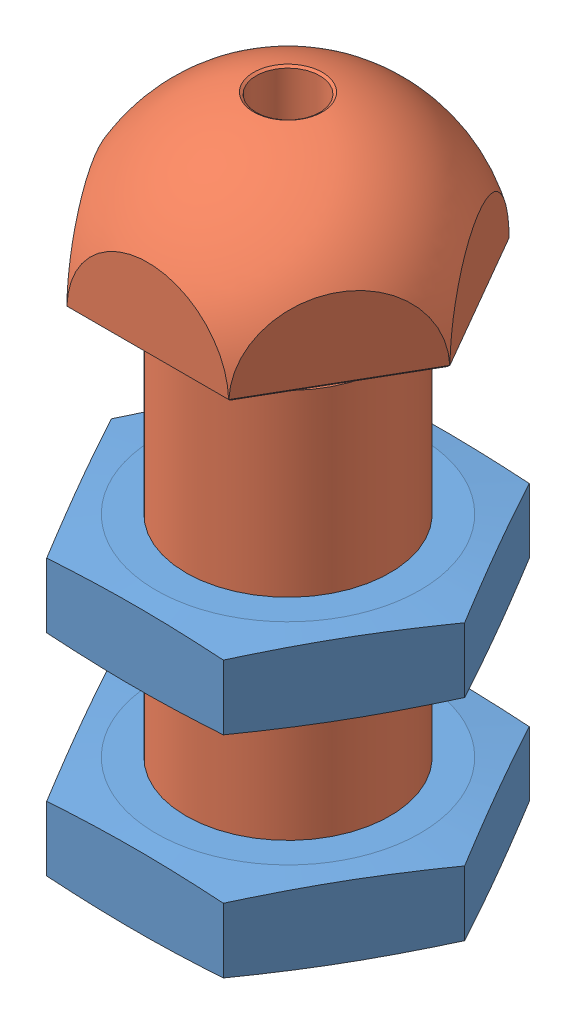
SolidWorks assembly ball_adjuster, configuration Default. Lengths in mm.
Overall size (27.71 52.41 24).
3 component instances, 2 part files, 4 mates.
Components (placement in the parent):
- m16_nut-1: m16_nut [Default] at (-18.1418 13.4655 -4.6402) size (27.71 6 24)
- m16_nut-2: m16_nut [Default] at (-18.1418 -3.0545 -4.6402) size (27.71 6 24)
- ball_adjuster-1: ball_adjuster [Default] at (-18.1418 -4.2845 -4.6402) size (25.4 52.41 22)
Mates (geometry in assembly coordinates):
- Concentric3: concentric anti-aligned: cylinder of m16_nut-1 through (-18.1418 19.4655 -4.6402) axis (0 1 0) radius 7.25; cylinder of ball_adjuster-1 through (-18.1418 -4.2845 -4.6402) axis (0 -1 0) radius 8
- Concentric4: concentric anti-aligned: cylinder of m16_nut-2 through (-18.1418 5.3055 -4.6402) axis (0 1 0) radius 7.25; cylinder of ball_adjuster-1 through (-18.1418 -4.2845 -4.6402) axis (0 -1 0) radius 8
- Distance8: distance = 16.25 mm anti-aligned: plane of ball_adjuster-1 through (-10.1418 35.7155 -4.6402) normal (0 -1 0); plane of m16_nut-1 through (-18.1418 19.4655 -4.6402) normal (0 1 0)
- Distance9: distance = 10.52 mm anti-aligned: plane of m16_nut-1 through (-18.1418 13.4655 -4.6402) normal (0 -1 0); plane of m16_nut-2 through (-18.1418 2.9455 -4.6402) normal (0 1 0)
